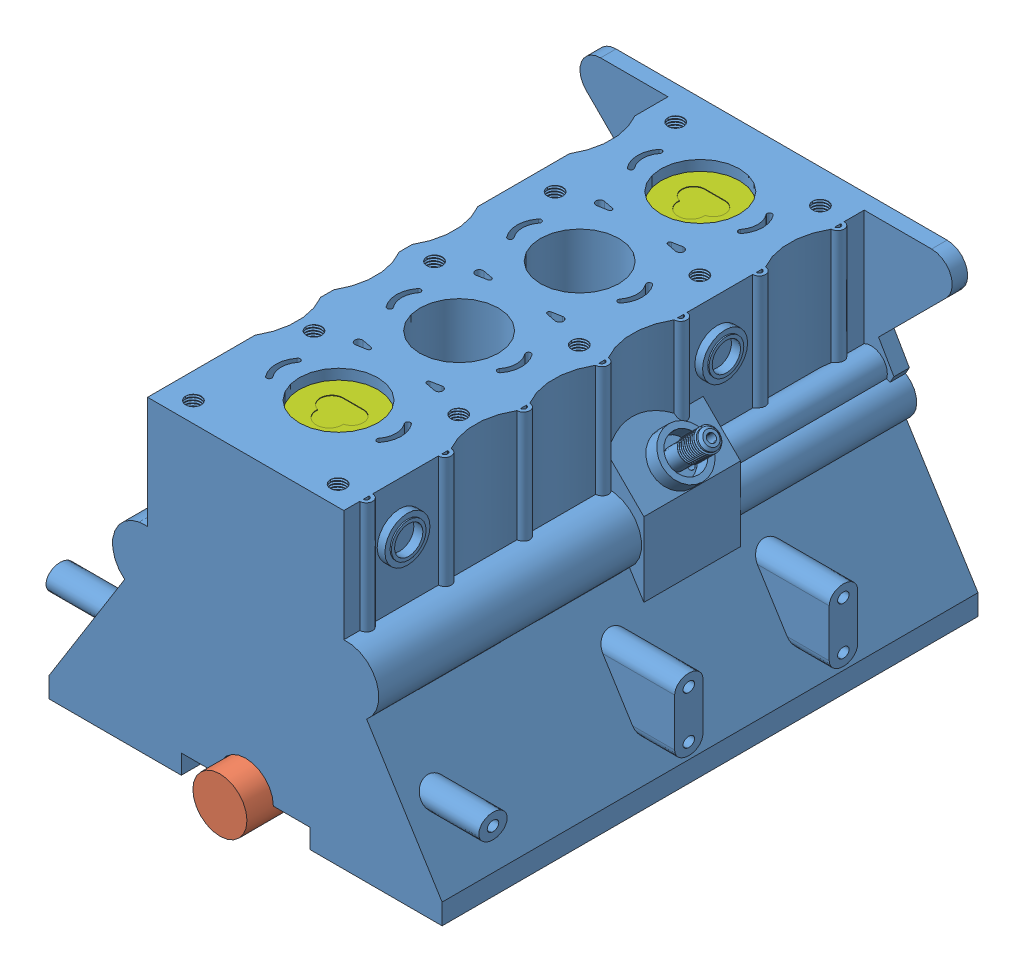
SolidWorks assembly Assem1, configuration Default. Lengths in mm.
Overall size (336 296.53 456).
22 component instances, 7 part files, 41 mates.
Components (placement in the parent):
- engine_block-1: engine_block [Default] at (-22.5193 99.0569 -198.9777) size (336 241.06 416)
- crankshaft-1: crankshaft [Default] at (-35.2702 -79.4806 -165.8777) x (-0.863583 -0.504207 0) z (0 0 1) size (68.12 118.48 456)
- con rod a1-1: con rod a1 [Default] at (-40.2565 -30.4916 150.9223) x (-0.980102 0.198494 0) z (0 0 -1) size (62 132.5 16)
- con rod a2-1: con rod a2 [Default] at (-31.4676 -87.3137 150.9223) x (0.874332 0.485328 0) z (0 0 -1) size (29 14.5 16)
- con rod a3-1: con rod a3 [Default] at (-40.2565 -30.4916 150.9223) x (-0.980102 0.198494 0) z (0 0 -1) size (62 25.14 16)
- con rod a4-1: con rod a4 [Default] at (-31.4676 -87.3137 150.9223) x (0.874332 0.485328 0) z (0 0 -1) size (29 14.5 16)
- piston head-1: piston head [Default] at (-22.5193 80.7963 144.9223) x (-1 0 0) z (0 0 -1) size (61 72.16 61)
- piston head-3: piston head [Default] at (-22.5193 -0.7971 51.3223) x (-1 0 0) z (0 0 -1) size (61 72.16 61)
- con rod a1-3: con rod a1 [Default] at (-4.7821 -112.0849 57.3223) x (-0.980102 -0.198494 0) z (0 0 -1) size (62 132.5 16)
- con rod a2-4: con rod a2 [Default] at (16.1711 -168.907 57.3223) x (0.874332 0.485328 0) z (0 0 -1) size (29 14.5 16)
- con rod a4-3: con rod a4 [Default] at (16.1711 -168.907 57.3223) x (0.874332 0.485328 0) z (0 0 -1) size (29 14.5 16)
- con rod a1-5: con rod a1 [Default] at (-4.7821 -112.0849 -36.2777) x (-0.980102 -0.198494 0) z (0 0 -1) size (62 132.5 16)
- con rod a4-4: con rod a4 [Default] at (7.414 -172.1415 -36.2777) x (0.979891 0.199535 0) z (0 0 -1) size (29 14.5 16)
- con rod a1-6: con rod a1 [Default] at (-40.2565 -30.4916 -129.8777) x (-0.980102 0.198494 0) z (0 0 -1) size (62 132.5 16)
- piston head-4: piston head [Default] at (-22.5193 -0.7971 -42.2777) x (-1 0 0) z (0 0 -1) size (61 72.16 61)
- piston head-5: piston head [Default] at (-22.5193 80.7963 -135.8777) x (-1 0 0) z (0 0 -1) size (61 72.16 61)
- con rod a2-5: con rod a2 [Default] at (7.414 -172.1415 -36.2777) x (0.979891 0.199535 0) z (0 0 -1) size (29 14.5 16)
- con rod a2-6: con rod a2 [Default] at (-31.4676 -87.3137 -129.8777) x (0.874332 0.485328 0) z (0 0 -1) size (29 14.5 16)
- con rod a4-5: con rod a4 [Default] at (-31.4676 -87.3137 -129.8777) x (0.874332 0.485328 0) z (0 0 -1) size (29 14.5 16)
- con rod a3-3: con rod a3 [Default] at (-4.7821 -112.0849 57.3223) x (-0.980102 -0.198494 0) z (0 0 -1) size (62 25.14 16)
- con rod a3-4: con rod a3 [Default] at (-4.7821 -112.0849 -36.2777) x (-0.980102 -0.198494 0) z (0 0 -1) size (62 25.14 16)
- con rod a3-5: con rod a3 [Default] at (-40.2565 -30.4916 -129.8777) x (-0.980102 0.198494 0) z (0 0 -1) size (62 25.14 16)
Mates (geometry in assembly coordinates):
- Hinge1: hinge aligned: cylinder of crankshaft-1 through (-22.5193 -101.3198 4.5223) axis (0 0 1) radius 21; cylinder of crankshaft-1 through (-22.5193 -101.3198 276.0223) axis (0 0 -1) radius 21.5; plane of engine_block-1 through (-22.5193 -101.3198 -198.9777) normal (0 0 -1); plane of engine_block-1 through (-151.0193 108.7415 -198.9777) normal (0 0 -1)
- Hinge2: hinge aligned: cylinder of con rod a2-1 through (-46.3386 -60.5231 136.9123) axis (0 0 1) radius 14.5; cylinder of con rod a3-1 through (-46.3386 -60.5231 136.9123) axis (0 0 1) radius 14.5; plane of con rod a2-1 through (-46.3386 -60.5231 136.9223) normal (0 0 -1); plane of con rod a3-1 through (-46.3386 -60.5231 136.9223) normal (0 0 -1)
- Hinge3: hinge aligned: cylinder of con rod a4-1 through (-46.3386 -60.5231 136.9123) axis (0 0 1) radius 14.5; cylinder of con rod a1-1 through (-46.3386 -60.5231 136.9123) axis (0 0 1) radius 14.5; plane of con rod a1-1 through (-46.3386 -60.5231 136.9223) normal (0 0 -1); plane of con rod a4-1 through (-46.3386 -60.5231 136.9223) normal (0 0 -1)
- Concentric1: concentric anti-aligned: cylinder of con rod a1-1 through (-22.5193 57.0891 138.9223) axis (0 0 1) radius 7.5; cylinder of piston head-1 through (-22.5193 57.0891 175.4223) axis (0 0 -1) radius 8
- Width1: width anti-aligned: plane of piston head-1 through (-7.3332 47.7491 135.8299) normal (0 0 1); plane of piston head-1 through (-7.3332 47.7491 154.0148) normal (0 0 -1); plane of con rod a1-1 through (-22.5193 57.0891 137.4223) normal (0 0 -1); plane of con rod a1-1 through (-22.5193 57.0891 152.4223) normal (0 0 1)
- Concentric2: concentric aligned: cylinder of con rod a1-1 through (-67.6496 -44.8397 144.9223) axis (0.198494 0.980102 0) radius 5.5; cylinder of con rod a3-1 through (-67.6496 -44.8397 144.9223) axis (0.198494 0.980102 0) radius 5.5
- Concentric3: concentric aligned: cylinder of con rod a1-1 through (-20.6047 -54.3674 144.9223) axis (0.198494 0.980102 0) radius 5.5; cylinder of con rod a3-1 through (-20.6047 -54.3674 144.9223) axis (0.198494 0.980102 0) radius 5.5
- Coincident1: coincident anti-aligned: plane of con rod a1-1 through (-80.026 -53.7006 136.9123) normal (-0.198494 -0.980102 0); plane of con rod a3-1 through (-80.026 -53.7006 136.9123) normal (0.198494 0.980102 0)
- Coincident2: coincident anti-aligned: plane of con rod a2-1 through (-16.2867 -43.8418 136.9123) normal (0.485328 -0.874332 0); plane of con rod a4-1 through (-16.2867 -43.8418 136.9123) normal (-0.485328 0.874332 0)
- Concentric5: concentric aligned: cylinder of engine_block-1 through (-22.5193 99.7415 144.9223) axis (0 1 0) radius 30.5; cylinder of piston head-1 through (-22.5193 120.0476 144.9223) axis (0 1 0) radius 30.5
- Concentric6: concentric anti-aligned: cylinder of crankshaft-1 through (-46.3386 -60.5231 144.9223) axis (0 0 -1) radius 11; cylinder of con rod a4-1 through (-46.3386 -60.5231 138.9223) axis (0 0 1) radius 12
- Concentric8: concentric aligned: cylinder of con rod a1-3 through (22.611 -126.4331 51.3223) axis (-0.198494 0.980102 0) radius 5.5; cylinder of con rod a3-3 through (22.611 -126.4331 51.3223) axis (-0.198494 0.980102 0) radius 5.5
- Concentric9: concentric aligned: cylinder of con rod a1-3 through (-24.4339 -135.9608 51.3223) axis (-0.198494 0.980102 0) radius 5.5; cylinder of con rod a3-3 through (-24.4339 -135.9608 51.3223) axis (-0.198494 0.980102 0) radius 5.5
- Coincident3: coincident anti-aligned: plane of con rod a1-3 through (-32.3874 -148.939 43.3123) normal (0.198494 -0.980102 0); plane of con rod a3-3 through (-32.3874 -148.939 43.3123) normal (-0.198494 0.980102 0)
- Hinge5: hinge aligned: cylinder of con rod a4-3 through (1.3 -142.1164 43.3123) axis (0 0 1) radius 14.5; cylinder of con rod a3-3 through (1.3 -142.1164 43.3123) axis (0 0 1) radius 14.5; plane of con rod a3-3 through (1.3 -142.1164 59.3223) normal (0 0 1); plane of con rod a4-3 through (1.3 -142.1164 59.3223) normal (0 0 1)
- Hinge6: hinge aligned: cylinder of con rod a2-4 through (1.3 -142.1164 43.3123) axis (0 0 1) radius 14.5; cylinder of con rod a3-3 through (1.3 -142.1164 43.3123) axis (0 0 1) radius 14.5; plane of con rod a2-4 through (1.3 -142.1164 59.3223) normal (0 0 1); plane of con rod a3-3 through (1.3 -142.1164 59.3223) normal (0 0 1)
- Concentric11: concentric anti-aligned: cylinder of piston head-3 through (-22.5193 -24.5042 81.8223) axis (0 0 -1) radius 8; cylinder of con rod a1-3 through (-22.5193 -24.5042 45.3223) axis (0 0 1) radius 7.5
- Width3: width anti-aligned: plane of con rod a1-3 through (-22.5193 -24.5042 58.8223) normal (0 0 1); plane of con rod a1-3 through (-22.5193 -24.5042 43.8223) normal (0 0 -1); plane of piston head-3 through (-7.3332 -33.8442 60.4148) normal (0 0 -1); plane of piston head-3 through (-7.3332 -33.8442 42.2299) normal (0 0 1)
- Coincident4: coincident anti-aligned: plane of con rod a2-4 through (31.352 -125.4351 43.3123) normal (0.485328 -0.874332 0); plane of con rod a4-3 through (31.352 -125.4351 43.3123) normal (-0.485328 0.874332 0)
- Concentric12: concentric anti-aligned: cylinder of con rod a1-5 through (-22.5193 -24.5042 -48.2777) axis (0 0 1) radius 7.5; cylinder of piston head-4 through (-22.5193 -24.5042 -11.7777) axis (0 0 -1) radius 8
- Concentric13: concentric anti-aligned: cylinder of con rod a1-6 through (-22.5193 57.0891 -141.8777) axis (0 0 1) radius 7.5; cylinder of piston head-5 through (-22.5193 57.0891 -105.3777) axis (0 0 -1) radius 8
- Width4: width anti-aligned: plane of piston head-4 through (-7.3332 -33.8442 -33.1852) normal (0 0 -1); plane of piston head-4 through (-7.3332 -33.8442 -51.3701) normal (0 0 1); plane of con rod a1-5 through (-22.5193 -24.5042 -34.7777) normal (0 0 1); plane of con rod a1-5 through (-22.5193 -24.5042 -49.7777) normal (0 0 -1)
- Width5: width aligned: plane of con rod a1-6 through (-22.5193 57.0891 -128.3777) normal (0 0 1); plane of con rod a1-6 through (-22.5193 57.0891 -143.3777) normal (0 0 -1); plane of piston head-5 through (-7.3332 47.7491 -144.9701) normal (0 0 1); plane of piston head-5 through (-7.3332 47.7491 -126.7852) normal (0 0 -1)
- Concentric15: concentric aligned: cylinder of con rod a1-5 through (22.611 -126.4331 -42.2777) axis (-0.198494 0.980102 0) radius 5.5; cylinder of con rod a3-4 through (22.611 -126.4331 -42.2777) axis (-0.198494 0.980102 0) radius 5.5
- Concentric16: concentric aligned: cylinder of con rod a1-5 through (-24.4339 -135.9608 -42.2777) axis (-0.198494 0.980102 0) radius 5.5; cylinder of con rod a3-4 through (-24.4339 -135.9608 -42.2777) axis (-0.198494 0.980102 0) radius 5.5
- Coincident5: coincident anti-aligned: plane of con rod a1-5 through (-32.3874 -148.939 -50.2877) normal (0.198494 -0.980102 0); plane of con rod a3-4 through (-32.3874 -148.939 -50.2877) normal (-0.198494 0.980102 0)
- Concentric17: concentric aligned: cylinder of con rod a1-6 through (-67.6496 -44.8397 -135.8777) axis (0.198494 0.980102 0) radius 5.5; cylinder of con rod a3-5 through (-67.6496 -44.8397 -135.8777) axis (0.198494 0.980102 0) radius 5.5
- Concentric18: concentric aligned: cylinder of con rod a1-6 through (-20.6047 -54.3674 -135.8777) axis (0.198494 0.980102 0) radius 5.5; cylinder of con rod a3-5 through (-20.6047 -54.3674 -135.8777) axis (0.198494 0.980102 0) radius 5.5
- Coincident6: coincident anti-aligned: plane of con rod a1-6 through (-80.026 -53.7006 -143.8877) normal (-0.198494 -0.980102 0); plane of con rod a3-5 through (-80.026 -53.7006 -143.8877) normal (0.198494 0.980102 0)
- Hinge7: hinge aligned: cylinder of con rod a4-4 through (1.3 -142.1164 -50.2877) axis (0 0 1) radius 14.5; cylinder of con rod a3-4 through (1.3 -142.1164 -50.2877) axis (0 0 1) radius 14.5; plane of con rod a3-4 through (1.3 -142.1164 -34.2777) normal (0 0 1); plane of con rod a4-4 through (1.3 -142.1164 -34.2777) normal (0 0 1)
- Hinge8: hinge aligned: cylinder of con rod a2-5 through (1.3 -142.1164 -50.2877) axis (0 0 1) radius 14.5; cylinder of con rod a1-5 through (1.3 -142.1164 -50.2877) axis (0 0 1) radius 14.5; plane of con rod a1-5 through (1.3 -142.1164 -34.2777) normal (0 0 1); plane of con rod a2-5 through (1.3 -142.1164 -34.2777) normal (0 0 1)
- Coincident7: coincident anti-aligned: plane of con rod a4-4 through (34.9802 -135.2582 -50.2877) normal (-0.199535 0.979891 0); plane of con rod a2-5 through (34.9802 -135.2582 -50.2877) normal (0.199535 -0.979891 0)
- Hinge9: hinge aligned: cylinder of con rod a4-5 through (-46.3386 -60.5231 -143.8877) axis (0 0 1) radius 14.5; cylinder of con rod a3-5 through (-46.3386 -60.5231 -143.8877) axis (0 0 1) radius 14.5; plane of con rod a3-5 through (-46.3386 -60.5231 -127.8777) normal (0 0 1); plane of con rod a4-5 through (-46.3386 -60.5231 -127.8777) normal (0 0 1)
- Hinge10: hinge aligned: cylinder of con rod a2-6 through (-46.3386 -60.5231 -143.8877) axis (0 0 1) radius 14.5; cylinder of con rod a1-6 through (-46.3386 -60.5231 -143.8877) axis (0 0 1) radius 14.5; plane of con rod a2-6 through (-46.3386 -60.5231 -127.8777) normal (0 0 1); plane of con rod a1-6 through (-46.3386 -60.5231 -127.8777) normal (0 0 1)
- Coincident8: coincident anti-aligned: plane of con rod a2-6 through (-16.2867 -43.8418 -143.8877) normal (0.485328 -0.874332 0); plane of con rod a4-5 through (-16.2867 -43.8418 -143.8877) normal (-0.485328 0.874332 0)
- Concentric19: concentric aligned: cylinder of engine_block-1 through (-22.5193 99.7415 51.3223) axis (0 1 0) radius 30.5; cylinder of piston head-3 through (-22.5193 38.4542 51.3223) axis (0 1 0) radius 30.5
- Concentric20: concentric aligned: cylinder of engine_block-1 through (-22.5193 99.7415 -42.2777) axis (0 1 0) radius 30.5; cylinder of piston head-4 through (-22.5193 38.4542 -42.2777) axis (0 1 0) radius 30.5
- Concentric21: concentric aligned: cylinder of engine_block-1 through (-22.5193 99.7415 -135.8777) axis (0 1 0) radius 30.5; cylinder of piston head-5 through (-22.5193 120.0476 -135.8777) axis (0 1 0) radius 30.5
- Concentric22: concentric anti-aligned: cylinder of crankshaft-1 through (1.3 -142.1164 51.3223) axis (0 0 -1) radius 11; cylinder of con rod a2-4 through (1.3 -142.1164 45.3223) axis (0 0 1) radius 12
- Concentric23: concentric anti-aligned: cylinder of crankshaft-1 through (1.3 -142.1164 -42.2777) axis (0 0 -1) radius 11; cylinder of con rod a2-5 through (1.3 -142.1164 -48.2777) axis (0 0 1) radius 12
- Concentric24: concentric anti-aligned: cylinder of crankshaft-1 through (-46.3386 -60.5231 -135.8777) axis (0 0 -1) radius 11; cylinder of con rod a2-6 through (-46.3386 -60.5231 -141.8777) axis (0 0 1) radius 12
